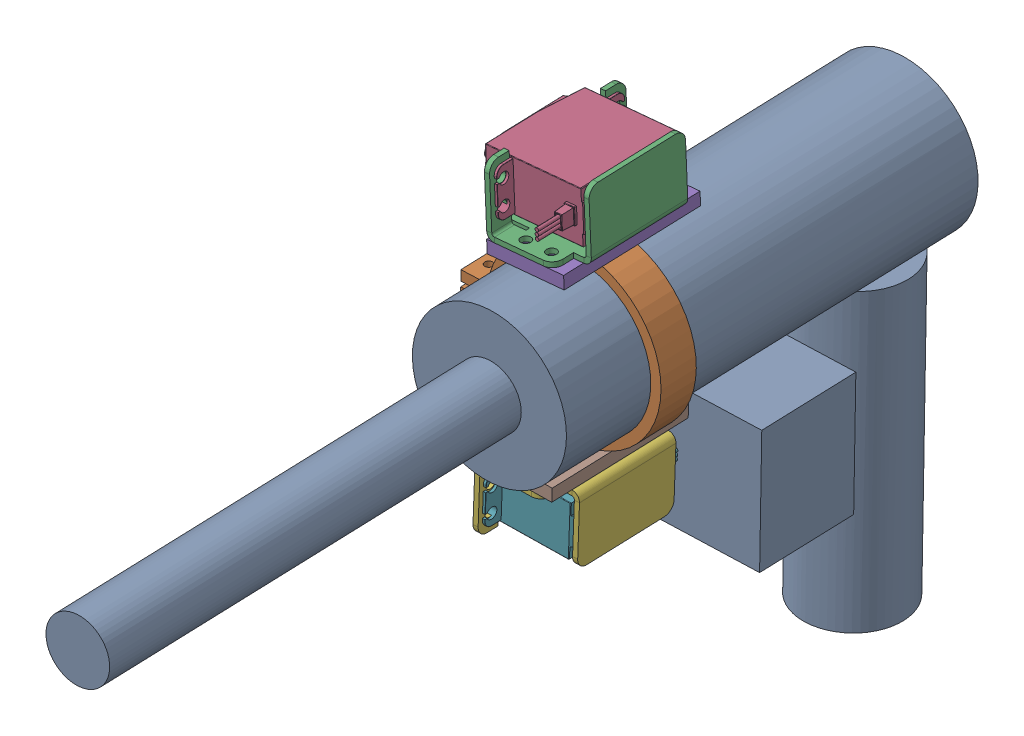
SolidWorks assembly assemblywithvac, configuration Default. Lengths in mm.
Overall size (96.68 228.57 356.99).
11 component instances, 6 part files, 8 mates.
Components (placement in the parent):
- vacuum! (2) (2)-1: vacuum! (2) (2) [Default] at (-44.9298 61.2578 -330.1524) x (0.999013 -0.00795 -0.043707) z (0.043785 0.009887 0.998992) size (80 179.49 352.01)
- RING-1: RING [Default] at (-38.0421 212.035 -200.1472) x (0.999041 0.00003 -0.043788) z (0.043785 0.009887 0.998992) size (78 68 15)
- Servomountassembly-1: Servomountassembly [Default] at (36.35 357.3401 -231.202) x (0.043785 0.009887 0.998992) z (0.224689 0.974235 -0.01949) size (63.92 53.06 39.89)
  - BRACKET-1: BRACKET [Défaut] at (23.7908 -34.1386 -116.3619) x (1 0 0) z (0 -0.961262 -0.275637) size (58 27 37.5)
  - SERVO-1: SERVO [Default] at (23.6864 -61.5912 -98.1352) x (0.001333 0.275637 -0.961261) z (-0.999999 0.000368 -0.001282) size (20 46.03 62.2)
  - plate-1: plate [Default] at (52.7908 -64.607 -130.3001) x (1 0 0) z (0 -0.275637 0.961262) size (58 30 5)
- Servomountassembly-2: Servomountassembly [Default] at (39.5593 68.7695 -178.5545) x (-0.043785 -0.009887 -0.998992) z (0.250472 -0.968123 -0.001397) size (63.92 53.06 39.89)
  - BRACKET-1: BRACKET [Défaut] at (23.7908 -34.1386 -116.3619) x (1 0 0) z (0 -0.961262 -0.275637) size (58 27 37.5)
  - SERVO-1: SERVO [Default] at (23.6864 -61.5912 -98.1352) x (0.001333 0.275637 -0.961261) z (-0.999999 0.000368 -0.001282) size (20 46.03 62.2)
  - plate-1: plate [Default] at (52.7908 -64.607 -130.3001) x (1 0 0) z (0 -0.275637 0.961262) size (58 30 5)
- GEAR-1: GEAR [Default] at (-70.5303 158.6556 -208.8031) x (0.043576 0.001836 0.999048) z (-0.998708 0.026266 0.043513) size (18.21 18.21 5.97)
Mates (geometry in assembly coordinates):
- Coincident1: coincident anti-aligned: cylinder of vacuum! (2) (2)-1 through (-36.1447 212.4635 -156.8573) axis (-0.043785 -0.009887 -0.998992) radius 30; circle of RING-1
- Tangent6: tangent anti-aligned: cylinder of RING-1 through (-37.7137 212.1092 -192.6547) axis (-0.043785 -0.009887 -0.998992) radius 34; plane of Servomountassembly-1/plate-1 through (-53.507 245.4762 -173.3125) normal (0.052333 -0.998601 0.007589)
- Parallel1: parallel aligned: cylinder of vacuum! (2) (2)-1 through (-36.1447 212.4635 -156.8573) axis (-0.043785 -0.009887 -0.998992) radius 30; line of Servomountassembly-1/plate-1 through (-23.8386 252.0276 -174.6777) axis (-0.043785 -0.009887 -0.998992)
- Lock2: lock: unknown of RING-1; unknown of Servomountassembly-1/plate-1
- Tangent10: tangent: circle of RING-1; plane of Servomountassembly-2/plate-1 through (-57.8722 178.2241 -228.2115) normal (0.025809 0.999606 -0.011024)
- Parallel4: parallel aligned: cylinder of vacuum! (2) (2)-1 through (-36.1447 212.4635 -156.8573) axis (-0.043785 -0.009887 -0.998992) radius 30; line of Servomountassembly-2/plate-1 through (-55.3327 178.7976 -170.2699) axis (-0.043785 -0.009887 -0.998992)
- Lock3: lock: unknown of RING-1; unknown of Servomountassembly-2/plate-1
- Concentric5: concentric anti-aligned: circle of Servomountassembly-2/SERVO-1; circle of GEAR-1
